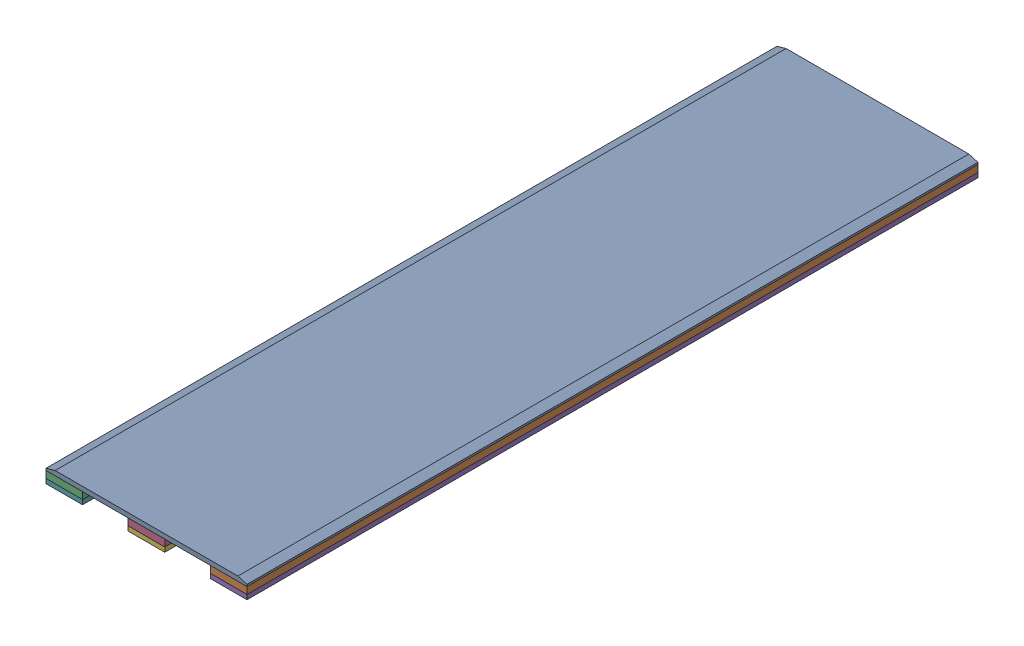
SolidWorks assembly GE-15019_ASM, configuration Default. Lengths in mm.
Overall size (558.8 44.45 2032).
7 component instances, 3 part files, 0 mates.
Components (placement in the parent):
- GE-15019-01-1: GE-15019-01 [Default] at origin size (558.8 12.7 2032)
- GE-15019-02-1: GE-15019-02 [Default] at (457.2 -19.05 0) size (101.6 19.05 2032)
- GE-15019-02-2: GE-15019-02 [Default] at (0 -19.05 0) size (101.6 19.05 2032)
- GE-15019-02-3: GE-15019-02 [Default] at (228.6 -19.05 0) size (101.6 19.05 2032)
- GE-15019-03-1: GE-15019-03 [Default] at (457.2 -31.75 0) size (101.6 12.7 2032)
- GE-15019-03-2: GE-15019-03 [Default] at (228.6 -31.75 0) size (101.6 12.7 2032)
- GE-15019-03-3: GE-15019-03 [Default] at (0 -31.75 0) size (101.6 12.7 2032)
